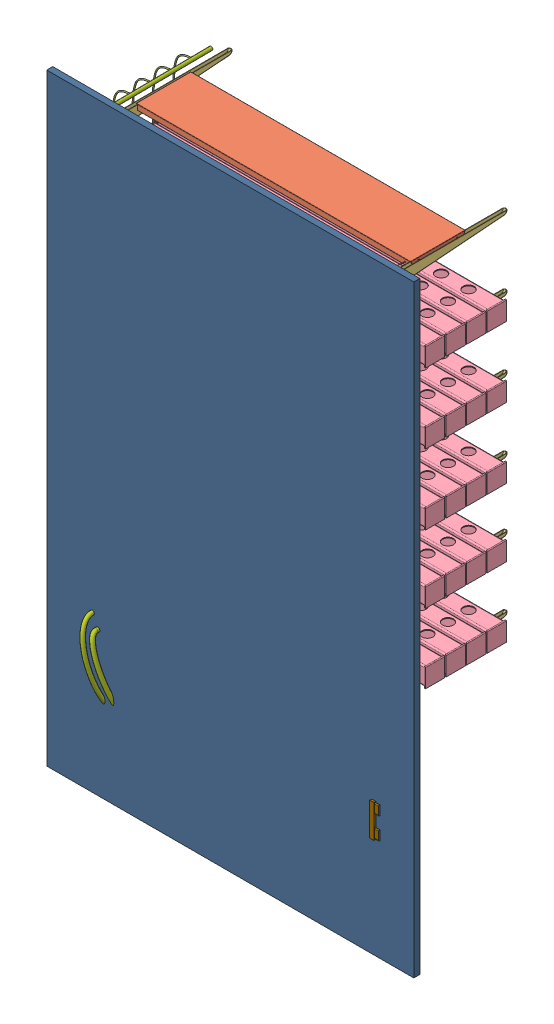
SolidWorks assembly C-W-1000, configuration Default. Lengths in mm.
Overall size (1339.66 2200 561.29).
63 component instances, 12 part files, 172 mates.
Components (placement in the parent):
- TSU-W-1: TSU-W [Default] at (502.4204 125.5072 -21.5071) size (25 1984 15)
- TSU-W-2: TSU-W [Default] at (-507.5796 125.5072 -25) size (25 1984 15)
- TSS-1000-10: TSS-1000 [Default] at (-2.5796 828.0993 -246.5218) size (1014.96 37.01 331.17)
- TSUB-1: TSUB [Default] at (502.4204 776.5993 -21.5071) x (-1 0 0) z (0 0 -1) size (14.07 50.86 484.03)
- TSUB-2: TSUB [Default] at (-507.5796 776.5993 -25) x (-1 0 0) z (0 0 -1) size (14.07 50.86 484.03)
- TSUB-3: TSUB [Default] at (-505 1030.7796 -25) x (-1 0 0) z (0 0 -1) size (14.07 50.86 484.03)
- TSUB-4: TSUB [Default] at (502.4801 1030.7796 -21.5071) x (-1 0 0) z (0 0 -1) size (14.07 50.86 484.03)
- TSS-1000-9: TSS-1000 [Default] at (-2.5199 1082.2796 -246.5218) size (1014.96 37.01 331.17)
- TSUB-5: TSUB [Default] at (-505 1534.5 -25) x (-1 0 0) z (0 0 -1) size (14.07 50.86 484.03)
- TSUB-6: TSUB [Default] at (502.4801 1534.5 -21.5071) x (-1 0 0) z (0 0 -1) size (14.07 50.86 484.03)
- TSS-1000-3: TSS-1000 [Default] at (-2.5199 1586 -246.5218) size (1014.96 37.01 331.17)
- TSUB-7: TSUB [Default] at (-505 2046.5 -25) x (-1 0 0) z (0 0 -1) size (14.07 50.86 484.03)
- TSUB-8: TSUB [Default] at (502.0186 2046.5 -21.5071) x (-1 0 0) z (0 0 -1) size (14.07 50.86 484.03)
- TSS-1000-7: TSS-1000 [Default] at (-2.9814 2098 -246.5218) size (1014.96 37.01 331.17)
- TSUB-9: TSUB [Default] at (-505 1278.5 -25) x (-1 0 0) z (0 0 -1) size (14.07 50.86 484.03)
- TSUB-10: TSUB [Default] at (502.4801 1278.5 -21.5071) x (-1 0 0) z (0 0 -1) size (14.07 50.86 484.03)
- TSS-1000-8: TSS-1000 [Default] at (-2.5199 1330 -246.5218) size (1014.96 37.01 331.17)
- TSUB-11: TSUB [Default] at (-505 1790.5 -25) x (-1 0 0) z (0 0 -1) size (14.07 50.86 484.03)
- TSUB-12: TSUB [Default] at (502.4801 1790.5 -21.5071) x (-1 0 0) z (0 0 -1) size (14.07 50.86 484.03)
- TSS-1000-6: TSS-1000 [Default] at (-2.5199 1842 -246.5218) size (1014.96 37.01 331.17)
- GB-1000-b-30: GB-1000-b [Default] at (0 1114.7796 -281.3342) size (1206 70 70)
- GB-600-p-1: GB-600-p [Default] at (-200 1114.7796 -281.3342) size (92 218.31 4)
- GB-600-p-2: GB-600-p [Default] at (-200 1114.7796 -356.3342) size (92 218.31 4)
- GB-1000-b-29: GB-1000-b [Default] at (0 1114.7796 -356.3342) size (1206 70 70)
- GB-600-p-3: GB-600-p [Default] at (-200 1114.7796 -131.3342) size (92 218.31 4)
- GB-1000-b-28: GB-1000-b [Default] at (0 1114.7796 -131.3342) size (1206 70 70)
- GB-600-p-4: GB-600-p [Default] at (-200 1114.7796 -206.3342) size (92 218.31 4)
- GB-1000-b-27: GB-1000-b [Default] at (0 1114.7796 -206.3342) size (1206 70 70)
- GB-1000-b-26: GB-1000-b [Default] at (0 860.5993 -131.3342) size (1206 70 70)
- GB-1000-b-25: GB-1000-b [Default] at (0 860.5993 -206.3342) size (1206 70 70)
- GB-1000-b-24: GB-1000-b [Default] at (0 860.5993 -281.3342) size (1206 70 70)
- GB-1000-b-23: GB-1000-b [Default] at (0 860.5993 -356.3342) size (1206 70 70)
- GB-1000-b-22: GB-1000-b [Default] at (0 1618.5 -131.3342) size (1206 70 70)
- GB-1000-b-15: GB-1000-b [Default] at (0 1618.5 -206.3342) size (1206 70 70)
- GB-1000-b-21: GB-1000-b [Default] at (0 1618.5 -281.3342) size (1206 70 70)
- GB-1000-b-31: GB-1000-b [Default] at (0 1618.5 -356.3342) size (1206 70 70)
- GB-600-p-5: GB-600-p [Default] at (-200 1618.5 -131.3342) size (92 218.31 4)
- GB-600-p-6: GB-600-p [Default] at (-200 1618.5 -206.3342) size (92 218.31 4)
- GB-600-p-7: GB-600-p [Default] at (-200 1618.5 -281.3342) size (92 218.31 4)
- GB-600-p-8: GB-600-p [Default] at (-200 1618.5 -356.3342) size (92 218.31 4)
- GB-600-p-9: GB-600-p [Default] at (-200 1362.5 -356.3342) size (92 218.31 4)
- GB-600-p-10: GB-600-p [Default] at (-200 1362.5 -281.3342) size (92 218.31 4)
- GB-600-p-11: GB-600-p [Default] at (-200 1362.5 -206.3342) size (92 218.31 4)
- GB-600-p-12: GB-600-p [Default] at (-200 1362.5 -131.3342) size (92 218.31 4)
- GB-1000-b-32: GB-1000-b [Default] at (0 1362.5 -356.3342) size (1206 70 70)
- GB-1000-b-38: GB-1000-b [Default] at (0 1362.5 -281.3342) size (1206 70 70)
- GB-1000-b-33: GB-1000-b [Default] at (0 1362.5 -206.3342) size (1206 70 70)
- GB-1000-b-34: GB-1000-b [Default] at (0 1362.5 -131.3342) size (1206 70 70)
- GB-600-p-13: GB-600-p [Default] at (-200 1874.5 -356.3342) size (92 218.31 4)
- GB-600-p-14: GB-600-p [Default] at (-200 1874.5 -281.3342) size (92 218.31 4)
- GB-600-p-15: GB-600-p [Default] at (-200 1874.5 -206.3342) size (92 218.31 4)
- GB-600-p-16: GB-600-p [Default] at (-200 1874.5 -131.3342) size (92 218.31 4)
- GB-1000-b-35: GB-1000-b [Default] at (0 1874.5 -131.3342) size (1206 70 70)
- GB-1000-b-36: GB-1000-b [Default] at (0 1874.5 -206.3342) size (1206 70 70)
- GB-1000-b-37: GB-1000-b [Default] at (0 1874.5 -281.3342) size (1206 70 70)
- GB-1000-b-39: GB-1000-b [Default] at (0 1874.5 -356.3342) size (1206 70 70)
- WT-1: WT [Default] at (-201.8616 320 -221.5071) size (600 370 400)
- Plumbing-1: Plumbing [Default] at (-504.0362 123.4725 -23.2262) x (0.99996 0 -0.008889) z (0.008889 0 0.99996) size (241.4 2067.5 489.85)
- Wire-1: Wire [Default] at (205.8727 2074.2018 -246.5277) x (-1 0 0) z (0 -1 0) size (2 2 1357)
- CCD-1: CCD [Default] at (502.4204 125.5072 -21.5071) x (0 0 -1) z (1 0 0) size (82.56 307.09 97.63) (hidden)
- Pump_LongWire-1: Pump_LongWire [Default] at (-201.8616 5 -221.5071) x (1 0 0) z (0 1 0) size (1045.87 220.37 364.08) (hidden)
- power brick-1: power brick [Default] at (516.0203 148.5195 -25) x (0 0 -1) z (1 0 0) size (82.62 120 30)
- Part2^C-W-1000-1: Part2^C-W-1000 [Default] x (1 0 0) z (0 1 0) size (1339.66 21.96 2200) (virtual)
Mates (geometry in assembly coordinates):
- Coincident41: coincident anti-aligned: plane of TSU-W-1 through (495.4204 797.5072 -6.5071) normal (1 0 0); plane of TSUB-1 through (495.4204 776.5993 -21.5071) normal (-1 0 0)
- Coincident42: coincident anti-aligned: plane of TSU-W-1 through (502.4204 2109.5072 -21.5071) normal (0 0 -1); plane of TSUB-1 through (509.4204 776.5993 -21.5071) normal (0 0 1)
- Parallel8: parallel: line of TSU-F-L-P-1 through (509 342 -23.5) axis (0 0 -1); plane of TSUB-1 through (498 816.5 -25) normal (0 1 0)
- Coincident44: coincident anti-aligned: plane of TSS-1000-10 through (496.9204 808.0993 -246.5218) normal (-1 0 0); plane of TSUB-1 through (496.9204 776.5993 -21.5071) normal (1 0 0)
- Coincident45: coincident anti-aligned: plane of TSS-1000-10 through (498.4204 826.5993 -148.0218) normal (0 -1 0); plane of TSUB-1 through (495.4204 826.5993 -21.5071) normal (0 1 0)
- Coincident46: coincident anti-aligned: plane of TSU-W-2 through (-514.5796 765.5072 -10) normal (1 0 0); plane of TSUB-2 through (-514.5796 776.5993 -25) normal (-1 0 0)
- Coincident47: coincident anti-aligned: plane of TSU-W-2 through (-507.5796 2109.5072 -25) normal (0 0 -1); plane of TSUB-2 through (-514.5796 776.5993 -25) normal (0 0 1)
- Coincident48: coincident anti-aligned: plane of TSS-1000-10 through (498.4204 826.5993 -148.0218) normal (0 -1 0); plane of TSUB-2 through (-514.5796 826.5993 -25) normal (0 1 0)
- Coincident49: coincident: plane of TSU-F-L-P-1 through (512 1041.5 0.001) normal (-1 0 0); plane of TSUB-4 through (512 1022.5 -25) normal (1 0 0)
- Coincident50: coincident anti-aligned: plane of TSU-W-1 through (502.4204 2109.5072 -21.5071) normal (0 0 -1); plane of TSUB-4 through (509.4801 1030.7796 -21.5071) normal (0 0 1)
- Coincident51: coincident: plane of TSU-F-L-P-2 through (-498 1073.5 0.001) normal (-1 0 0); plane of TSUB-3 through (-498 1022.5 -25) normal (1 0 0)
- Coincident52: coincident anti-aligned: plane of TSU-W-2 through (-507.5796 2109.5072 -25) normal (0 0 -1); plane of TSUB-3 through (-512 1030.7796 -25) normal (0 0 1)
- Coincident53: coincident anti-aligned: plane of TSUB-4 through (495.4801 1080.7796 -21.5071) normal (0 1 0); plane of TSS-1000-9 through (498.4801 1080.7796 -148.0218) normal (0 -1 0)
- Coincident54: coincident anti-aligned: plane of TSUB-3 through (-512 1080.7796 -25) normal (0 1 0); plane of TSS-1000-9 through (498.4801 1080.7796 -148.0218) normal (0 -1 0)
- Coincident55: coincident anti-aligned: plane of TSUB-4 through (496.9801 1030.7796 -21.5071) normal (1 0 0); plane of TSS-1000-9 through (496.9801 1062.2796 -246.5218) normal (-1 0 0)
- Coincident56: coincident anti-aligned: plane of TSUB-6 through (496.9801 1534.5 -21.5071) normal (1 0 0); plane of TSS-1000-3 through (496.9801 1566 -246.5218) normal (-1 0 0)
- Coincident57: coincident anti-aligned: plane of TSUB-6 through (495.4801 1584.5 -21.5071) normal (0 1 0); plane of TSS-1000-3 through (498.4801 1584.5 -148.0218) normal (0 -1 0)
- Coincident58: coincident anti-aligned: plane of TSUB-5 through (-512 1584.5 -25) normal (0 1 0); plane of TSS-1000-3 through (498.4801 1584.5 -148.0218) normal (0 -1 0)
- Coincident59: coincident anti-aligned: plane of TSUB-8 through (496.5186 2046.5 -21.5071) normal (1 0 0); plane of TSS-1000-7 through (496.5186 2078 -246.5218) normal (-1 0 0)
- Coincident60: coincident anti-aligned: plane of TSUB-8 through (495.0186 2096.5 -21.5071) normal (0 1 0); plane of TSS-1000-7 through (498.0186 2096.5 -148.0218) normal (0 -1 0)
- Coincident61: coincident anti-aligned: plane of TSUB-7 through (-512 2096.5 -25) normal (0 1 0); plane of TSS-1000-7 through (498.0186 2096.5 -148.0218) normal (0 -1 0)
- Coincident62: coincident anti-aligned: plane of TSUB-10 through (496.9801 1278.5 -21.5071) normal (1 0 0); plane of TSS-1000-8 through (496.9801 1310 -246.5218) normal (-1 0 0)
- Coincident63: coincident anti-aligned: plane of TSUB-10 through (495.4801 1328.5 -21.5071) normal (0 1 0); plane of TSS-1000-8 through (498.4801 1328.5 -148.0218) normal (0 -1 0)
- Coincident64: coincident anti-aligned: plane of TSUB-9 through (-512 1328.5 -25) normal (0 1 0); plane of TSS-1000-8 through (498.4801 1328.5 -148.0218) normal (0 -1 0)
- Coincident65: coincident anti-aligned: plane of TSUB-12 through (496.9801 1790.5 -21.5071) normal (1 0 0); plane of TSS-1000-6 through (496.9801 1822 -246.5218) normal (-1 0 0)
- Coincident66: coincident anti-aligned: plane of TSUB-12 through (495.4801 1840.5 -21.5071) normal (0 1 0); plane of TSS-1000-6 through (498.4801 1840.5 -148.0218) normal (0 -1 0)
- Coincident67: coincident anti-aligned: plane of TSUB-11 through (-512 1840.5 -25) normal (0 1 0); plane of TSS-1000-6 through (498.4801 1840.5 -148.0218) normal (0 -1 0)
- Coincident70: coincident anti-aligned: plane of TSU-W-1 through (502.4204 2109.5072 -21.5071) normal (0 0 -1); plane of TSUB-10 through (495.4801 1278.5 -21.5071) normal (0 0 1)
- Coincident71: coincident anti-aligned: plane of TSU-W-2 through (-507.5796 2109.5072 -25) normal (0 0 -1); plane of TSUB-9 through (-512 1278.5 -25) normal (0 0 1)
- Coincident72: coincident aligned: plane of TSUB-3 through (-498 1030.7796 -25) normal (1 0 0); plane of TSUB-9 through (-498 1278.5 -25) normal (1 0 0)
- Coincident73: coincident aligned: plane of TSUB-4 through (495.4801 1030.7796 -21.5071) normal (-1 0 0); plane of TSUB-10 through (495.4801 1278.5 -21.5071) normal (-1 0 0)
- Coincident74: coincident anti-aligned: plane of TSU-W-1 through (502.4204 2109.5072 -21.5071) normal (0 0 -1); plane of TSUB-6 through (495.4801 1534.5 -21.5071) normal (0 0 1)
- Coincident75: coincident anti-aligned: plane of TSU-W-2 through (-507.5796 2109.5072 -25) normal (0 0 -1); plane of TSUB-5 through (-512 1534.5 -25) normal (0 0 1)
- Coincident76: coincident aligned: plane of TSUB-5 through (-498 1534.5 -25) normal (1 0 0); plane of TSUB-9 through (-498 1278.5 -25) normal (1 0 0)
- Coincident78: coincident aligned: plane of TSUB-6 through (509.4801 1534.5 -21.5071) normal (1 0 0); plane of TSUB-12 through (509.4801 1790.5 -21.5071) normal (1 0 0)
- Coincident79: coincident aligned: plane of TSUB-6 through (495.4801 1534.5 -21.5071) normal (-1 0 0); plane of TSUB-10 through (495.4801 1278.5 -21.5071) normal (-1 0 0)
- Coincident80: coincident anti-aligned: plane of TSU-W-1 through (502.4204 2109.5072 -21.5071) normal (0 0 -1); plane of TSUB-12 through (495.4801 1790.5 -21.5071) normal (0 0 1)
- Coincident81: coincident: plane of TSU-F-L-P-2 through (-512 1873.5 0.001) normal (1 0 0); plane of TSUB-11 through (-512 1790.5 -25) normal (-1 0 0)
- Coincident82: coincident anti-aligned: plane of TSU-W-2 through (-507.5796 2109.5072 -25) normal (0 0 -1); plane of TSUB-11 through (-512 1790.5 -25) normal (0 0 1)
- Coincident83: coincident: plane of TSU-F-L-P-2 through (-512 1969.5 0.001) normal (1 0 0); plane of TSUB-7 through (-512 2046.5 -25) normal (-1 0 0)
- Coincident84: coincident anti-aligned: plane of TSU-W-2 through (-507.5796 2109.5072 -25) normal (0 0 -1); plane of TSUB-7 through (-512 2046.5 -25) normal (0 0 1)
- Coincident85: coincident: plane of TSU-F-L-P-1 through (498 2001.5 0.001) normal (1 0 0); plane of TSUB-8 through (498 2046.5 -25) normal (-1 0 0)
- Coincident86: coincident anti-aligned: plane of TSU-W-1 through (502.4204 2109.5072 -21.5071) normal (0 0 -1); plane of TSUB-8 through (495.0186 2046.5 -21.5071) normal (0 0 1)
- Coincident89: coincident: line of TSU-F-L-P-1 through (509 2070 -23.5) axis (0 0 -1); plane of TSUB-8 through (533.2603 2070 -25) normal (0 1 0)
- Coincident90: coincident aligned: plane of TSS-1000-7 through (498.0186 2098 -346.5218) normal (0 0 -1); plane of TSS-1000-6 through (498.4801 1842 -346.5218) normal (0 0 -1)
- Coincident91: coincident aligned: plane of TSS-1000-3 through (498.4801 1586 -346.5218) normal (0 0 -1); plane of TSS-1000-6 through (498.4801 1842 -346.5218) normal (0 0 -1)
- Coincident93: coincident aligned: plane of TSS-1000-3 through (498.4801 1586 -346.5218) normal (0 0 -1); plane of TSS-1000-8 through (498.4801 1330 -346.5218) normal (0 0 -1)
- Coincident94: coincident aligned: plane of TSS-1000-9 through (498.4801 1082.2796 -346.5218) normal (0 0 -1); plane of TSS-1000-8 through (498.4801 1330 -346.5218) normal (0 0 -1)
- Coincident95: coincident aligned: plane of TSS-1000-10 through (498.4204 828.0993 -346.5218) normal (0 0 -1); plane of TSS-1000-9 through (498.4801 1082.2796 -346.5218) normal (0 0 -1)
- Coincident153: coincident: line of TSU-F-L-P-1 through (512 1814 -23.5) axis (0 0 -1); plane of TSUB-12 through (533.2603 1814 -25) normal (0 1 0)
- Coincident155: coincident: line of TSU-F-L-P-1 through (512 1558 -23.5) axis (0 0 -1); plane of TSUB-6 through (533.2603 1558 -25) normal (0 1 0)
- Coincident157: coincident: line of TSU-F-L-P-1 through (512 1302 -23.5) axis (0 0 -1); plane of TSUB-10 through (533.2603 1302 -25) normal (0 1 0)
- Coincident159: coincident: line of TSU-F-L-P-1 through (512 1046 -23.5) axis (0 0 -1); plane of TSUB-4 through (533.2603 1046 -25) normal (0 1 0)
- Coincident167: coincident: line of TSU-F-L-P-1 through (512 790 -23.5) axis (0 0 -1); plane of TSUB-1 through (533.2603 790 -25) normal (0 1 0)
- Concentric31: concentric aligned: cylinder of GB-1000-b-24 through (-575 825.5983 -281.3342) axis (0 1 0) radius 4; cylinder of GB-600-p-1 through (-575 885.2796 -281.3342) axis (0 1 0) radius 2
- Distance1: distance = 10 mm aligned: plane of GB-600-p-1 through (-575 1095.2796 -281.3342) normal (0 1 0); plane of GB-1000-b-30 through (600 1085.2796 -248.8342) normal (0 1 0)
- Parallel10: parallel anti-aligned: plane of TSU-W-1 through (502.4204 2109.5072 -21.5071) normal (0 0 -1); plane of GB-1000-b-30 through (600 1082.2796 -248.8342) normal (0 0 1)
- Coincident201: coincident aligned: plane of GB-1000-b-30 through (0 1114.7796 -281.3342) normal (1 0 0)
- Coincident202: coincident anti-aligned: plane of TSS-1000-9 through (498.4801 1082.2796 -146.5218) normal (0 1 0); plane of GB-1000-b-30 through (600 1082.2796 -248.8342) normal (0 -1 0)
- Concentric32: concentric aligned: cylinder of GB-600-p-2 through (-575 885.2796 -356.3342) axis (0 1 0) radius 2; cylinder of GB-1000-b-29 through (-575 1079.7786 -356.3342) axis (0 1 0) radius 4
- Distance2: distance = 10 mm aligned: plane of GB-600-p-2 through (-575 1095.2796 -356.3342) normal (0 1 0); plane of GB-1000-b-29 through (600 1085.2796 -323.8342) normal (0 1 0)
- Concentric33: concentric aligned: cylinder of GB-600-p-3 through (-575 885.2796 -131.3342) axis (0 1 0) radius 2; cylinder of GB-1000-b-28 through (-575 1079.7786 -131.3342) axis (0 1 0) radius 4
- Distance3: distance = 10 mm aligned: plane of GB-600-p-3 through (-575 1095.2796 -131.3342) normal (0 1 0); plane of GB-1000-b-28 through (600 1085.2796 -98.8342) normal (0 1 0)
- Concentric34: concentric aligned: cylinder of GB-600-p-4 through (-575 885.2796 -206.3342) axis (0 1 0) radius 2; cylinder of GB-1000-b-27 through (-575 1079.7786 -206.3342) axis (0 1 0) radius 4
- Distance4: distance = 10 mm aligned: plane of GB-600-p-4 through (-575 1095.2796 -206.3342) normal (0 1 0); plane of GB-1000-b-27 through (600 1085.2796 -173.8342) normal (0 1 0)
- Coincident203: coincident anti-aligned: plane of TSS-1000-9 through (498.4801 1082.2796 -146.5218) normal (0 1 0); plane of GB-1000-b-29 through (600 1082.2796 -323.8342) normal (0 -1 0)
- Coincident204: coincident anti-aligned: plane of TSS-1000-9 through (498.4801 1082.2796 -146.5218) normal (0 1 0); plane of GB-1000-b-27 through (600 1082.2796 -173.8342) normal (0 -1 0)
- Coincident205: coincident anti-aligned: plane of TSS-1000-9 through (498.4801 1082.2796 -146.5218) normal (0 1 0); plane of GB-1000-b-28 through (600 1082.2796 -98.8342) normal (0 -1 0)
- Coincident206: coincident aligned: plane of GB-1000-b-30 through (603 1114.7796 -281.3342) normal (1 0 0); plane of GB-1000-b-27 through (603 1114.7796 -206.3342) normal (1 0 0)
- Coincident207: coincident aligned: plane of GB-1000-b-28 through (603 1114.7796 -131.3342) normal (1 0 0); plane of GB-1000-b-27 through (603 1114.7796 -206.3342) normal (1 0 0)
- Coincident208: coincident aligned: plane of GB-1000-b-30 through (603 1114.7796 -281.3342) normal (1 0 0); plane of GB-1000-b-29 through (603 1114.7796 -356.3342) normal (1 0 0)
- Distance5: distance = 10 mm anti-aligned: plane of GB-1000-b-27 through (600 1082.2796 -238.8342) normal (0 0 -1); plane of GB-1000-b-30 through (600 1082.2796 -248.8342) normal (0 0 1)
- Distance6: distance = 10 mm anti-aligned: plane of GB-1000-b-27 through (600 1082.2796 -173.8342) normal (0 0 1); plane of GB-1000-b-28 through (600 1082.2796 -163.8342) normal (0 0 -1)
- Distance7: distance = 10 mm anti-aligned: plane of GB-1000-b-30 through (600 1082.2796 -313.8342) normal (0 0 -1); plane of GB-1000-b-29 through (600 1082.2796 -323.8342) normal (0 0 1)
- Distance8: distance = 10 mm anti-aligned: plane of GB-1000-b-25 through (600 828.0993 -173.8342) normal (0 0 1); plane of GB-1000-b-26 through (600 828.0993 -163.8342) normal (0 0 -1)
- Distance9: distance = 10 mm anti-aligned: plane of GB-1000-b-25 through (600 828.0993 -238.8342) normal (0 0 -1); plane of GB-1000-b-24 through (600 828.0993 -248.8342) normal (0 0 1)
- Coincident212: coincident aligned: plane of GB-1000-b-26 through (603 860.5993 -131.3342) normal (1 0 0); plane of GB-1000-b-25 through (603 860.5993 -206.3342) normal (1 0 0)
- Coincident213: coincident aligned: plane of GB-1000-b-24 through (603 860.5993 -281.3342) normal (1 0 0); plane of GB-1000-b-23 through (603 860.5993 -356.3342) normal (1 0 0)
- Coincident214: coincident aligned: plane of GB-1000-b-25 through (603 860.5993 -206.3342) normal (1 0 0); plane of GB-1000-b-24 through (603 860.5993 -281.3342) normal (1 0 0)
- Distance10: distance = 10 mm anti-aligned: plane of GB-1000-b-24 through (600 828.0993 -313.8342) normal (0 0 -1); plane of GB-1000-b-23 through (600 828.0993 -323.8342) normal (0 0 1)
- Coincident215: coincident aligned: plane of GB-1000-b-24 through (600 828.0993 -248.8342) normal (0 -1 0); plane of GB-1000-b-23 through (600 828.0993 -323.8342) normal (0 -1 0)
- Coincident216: coincident aligned: plane of GB-1000-b-25 through (600 828.0993 -173.8342) normal (0 -1 0); plane of GB-1000-b-24 through (600 828.0993 -248.8342) normal (0 -1 0)
- Coincident217: coincident aligned: plane of GB-1000-b-26 through (600 828.0993 -98.8342) normal (0 -1 0); plane of GB-1000-b-25 through (600 828.0993 -173.8342) normal (0 -1 0)
- Coincident218: coincident anti-aligned: plane of TSS-1000-10 through (498.4204 828.0993 -146.5218) normal (0 1 0); plane of GB-1000-b-24 through (600 828.0993 -248.8342) normal (0 -1 0)
- Concentric35: concentric aligned: cylinder of GB-600-p-2 through (-575 885.2796 -356.3342) axis (0 1 0) radius 2; cylinder of GB-1000-b-23 through (-575 825.5983 -356.3342) axis (0 1 0) radius 4
- Concentric36: concentric aligned: cylinder of GB-1000-b-22 through (-575 1583.499 -131.3342) axis (0 1 0) radius 4; cylinder of GB-600-p-5 through (-575 1389 -131.3342) axis (0 1 0) radius 2
- Distance11: distance = 10 mm anti-aligned: plane of GB-1000-b-15 through (600 1586 -173.8342) normal (0 0 1); plane of GB-1000-b-22 through (600 1586 -163.8342) normal (0 0 -1)
- Concentric37: concentric aligned: cylinder of GB-1000-b-31 through (-575 1583.499 -356.3342) axis (0 1 0) radius 4; cylinder of GB-600-p-8 through (-575 1389 -356.3342) axis (0 1 0) radius 2
- Concentric38: concentric aligned: cylinder of GB-1000-b-21 through (-575 1583.499 -281.3342) axis (0 1 0) radius 4; cylinder of GB-600-p-7 through (-575 1389 -281.3342) axis (0 1 0) radius 2
- Distance12: distance = 10 mm aligned: plane of GB-600-p-7 through (-575 1599 -281.3342) normal (0 1 0); plane of GB-1000-b-21 through (600 1589 -248.8342) normal (0 1 0)
- Distance13: distance = 10 mm anti-aligned: plane of GB-1000-b-15 through (600 1586 -238.8342) normal (0 0 -1); plane of GB-1000-b-21 through (600 1586 -248.8342) normal (0 0 1)
- Concentric39: concentric aligned: cylinder of GB-1000-b-15 through (-575 1583.499 -206.3342) axis (0 1 0) radius 4; cylinder of GB-600-p-6 through (-575 1389 -206.3342) axis (0 1 0) radius 2
- Distance14: distance = 10 mm aligned: plane of GB-600-p-8 through (-575 1599 -356.3342) normal (0 1 0); plane of GB-1000-b-31 through (600 1589 -323.8342) normal (0 1 0)
- Distance15: distance = 10 mm aligned: plane of GB-600-p-5 through (-575 1599 -131.3342) normal (0 1 0); plane of GB-1000-b-22 through (600 1589 -98.8342) normal (0 1 0)
- Distance16: distance = 10 mm aligned: plane of GB-600-p-6 through (-575 1599 -206.3342) normal (0 1 0); plane of GB-1000-b-15 through (600 1589 -173.8342) normal (0 1 0)
- Coincident220: coincident aligned: plane of GB-1000-b-22 through (603 1618.5 -131.3342) normal (1 0 0); plane of GB-1000-b-15 through (603 1618.5 -206.3342) normal (1 0 0)
- Coincident221: coincident aligned: plane of GB-1000-b-21 through (603 1618.5 -281.3342) normal (1 0 0); plane of GB-1000-b-31 through (603 1618.5 -356.3342) normal (1 0 0)
- Coincident222: coincident aligned: plane of GB-1000-b-15 through (603 1618.5 -206.3342) normal (1 0 0); plane of GB-1000-b-21 through (603 1618.5 -281.3342) normal (1 0 0)
- Distance17: distance = 10 mm anti-aligned: plane of GB-1000-b-21 through (600 1586 -313.8342) normal (0 0 -1); plane of GB-1000-b-31 through (600 1586 -323.8342) normal (0 0 1)
- Coincident223: coincident aligned: plane of GB-1000-b-31 through (600 1586 -323.8342) normal (0 -1 0); plane of GB-1000-b-22 through (600 1586 -98.8342) normal (0 -1 0)
- Coincident224: coincident aligned: plane of GB-1000-b-22 through (600 1586 -98.8342) normal (0 -1 0); plane of GB-1000-b-15 through (600 1586 -173.8342) normal (0 -1 0)
- Coincident225: coincident aligned: plane of GB-1000-b-15 through (600 1586 -173.8342) normal (0 -1 0); plane of GB-1000-b-21 through (600 1586 -248.8342) normal (0 -1 0)
- Coincident226: coincident aligned: plane of GB-1000-b-33 through (600 1330 -173.8342) normal (0 -1 0); plane of GB-1000-b-34 through (600 1330 -98.8342) normal (0 -1 0)
- Coincident227: coincident aligned: plane of GB-1000-b-38 through (600 1330 -248.8342) normal (0 -1 0); plane of GB-1000-b-33 through (600 1330 -173.8342) normal (0 -1 0)
- Coincident228: coincident aligned: plane of GB-1000-b-38 through (603 1362.5 -281.3342) normal (1 0 0); plane of GB-1000-b-33 through (603 1362.5 -206.3342) normal (1 0 0)
- Distance18: distance = 10 mm anti-aligned: plane of GB-1000-b-38 through (600 1330 -313.8342) normal (0 0 -1); plane of GB-1000-b-32 through (600 1330 -323.8342) normal (0 0 1)
- Coincident229: coincident aligned: plane of GB-1000-b-32 through (600 1330 -323.8342) normal (0 -1 0); plane of GB-1000-b-34 through (600 1330 -98.8342) normal (0 -1 0)
- Concentric40: concentric aligned: cylinder of GB-600-p-10 through (-575 1133 -281.3342) axis (0 1 0) radius 2; cylinder of GB-1000-b-38 through (-575 1327.499 -281.3342) axis (0 1 0) radius 4
- Distance19: distance = 10 mm aligned: plane of GB-600-p-11 through (-575 1343 -206.3342) normal (0 1 0); plane of GB-1000-b-33 through (600 1333 -173.8342) normal (0 1 0)
- Concentric41: concentric aligned: cylinder of GB-600-p-12 through (-575 1133 -131.3342) axis (0 1 0) radius 2; cylinder of GB-1000-b-34 through (-575 1327.499 -131.3342) axis (0 1 0) radius 4
- Distance20: distance = 10 mm aligned: plane of GB-600-p-12 through (-575 1343 -131.3342) normal (0 1 0); plane of GB-1000-b-34 through (600 1333 -98.8342) normal (0 1 0)
- Distance21: distance = 10 mm anti-aligned: plane of GB-1000-b-33 through (600 1330 -173.8342) normal (0 0 1); plane of GB-1000-b-34 through (600 1330 -163.8342) normal (0 0 -1)
- Coincident230: coincident aligned: plane of GB-1000-b-33 through (603 1362.5 -206.3342) normal (1 0 0); plane of GB-1000-b-34 through (603 1362.5 -131.3342) normal (1 0 0)
- Distance22: distance = 10 mm anti-aligned: plane of GB-1000-b-33 through (600 1330 -238.8342) normal (0 0 -1); plane of GB-1000-b-38 through (600 1330 -248.8342) normal (0 0 1)
- Concentric42: concentric aligned: cylinder of GB-600-p-9 through (-575 1133 -356.3342) axis (0 1 0) radius 2; cylinder of GB-1000-b-32 through (-575 1327.499 -356.3342) axis (0 1 0) radius 4
- Distance23: distance = 10 mm aligned: plane of GB-600-p-9 through (-575 1343 -356.3342) normal (0 1 0); plane of GB-1000-b-32 through (600 1333 -323.8342) normal (0 1 0)
- Distance24: distance = 10 mm aligned: plane of GB-600-p-10 through (-575 1343 -281.3342) normal (0 1 0); plane of GB-1000-b-38 through (600 1333 -248.8342) normal (0 1 0)
- Concentric43: concentric aligned: cylinder of GB-600-p-11 through (-575 1133 -206.3342) axis (0 1 0) radius 2; cylinder of GB-1000-b-33 through (-575 1327.499 -206.3342) axis (0 1 0) radius 4
- Coincident231: coincident aligned: plane of GB-1000-b-32 through (603 1362.5 -356.3342) normal (1 0 0); plane of GB-1000-b-38 through (603 1362.5 -281.3342) normal (1 0 0)
- Coincident232: coincident anti-aligned: plane of TSS-1000-8 through (498.4801 1330 -146.5218) normal (0 1 0); plane of GB-1000-b-32 through (600 1330 -323.8342) normal (0 -1 0)
- Coincident233: coincident aligned: plane of GB-1000-b-29 through (600 1082.2796 -388.8342) normal (0 0 -1); plane of GB-1000-b-32 through (600 1330 -388.8342) normal (0 0 -1)
- Coincident234: coincident aligned: plane of GB-1000-b-29 through (603 1114.7796 -356.3342) normal (1 0 0); plane of GB-1000-b-32 through (603 1362.5 -356.3342) normal (1 0 0)
- Coincident235: coincident anti-aligned: plane of TSS-1000-3 through (498.4801 1586 -146.5218) normal (0 1 0); plane of GB-1000-b-31 through (600 1586 -323.8342) normal (0 -1 0)
- Coincident236: coincident aligned: plane of GB-1000-b-32 through (-603 1362.5 -356.3342) normal (-1 0 0); plane of GB-1000-b-31 through (-603 1618.5 -356.3342) normal (-1 0 0)
- Coincident237: coincident aligned: plane of GB-1000-b-31 through (600 1586 -388.8342) normal (0 0 -1); plane of GB-1000-b-32 through (600 1330 -388.8342) normal (0 0 -1)
- Coincident238: coincident aligned: plane of GB-1000-b-35 through (600 1842 -98.8342) normal (0 -1 0); plane of GB-1000-b-36 through (600 1842 -173.8342) normal (0 -1 0)
- Coincident239: coincident aligned: plane of GB-1000-b-36 through (600 1842 -173.8342) normal (0 -1 0); plane of GB-1000-b-37 through (600 1842 -248.8342) normal (0 -1 0)
- Coincident240: coincident aligned: plane of GB-1000-b-36 through (603 1874.5 -206.3342) normal (1 0 0); plane of GB-1000-b-37 through (603 1874.5 -281.3342) normal (1 0 0)
- Distance25: distance = 10 mm anti-aligned: plane of GB-1000-b-37 through (600 1842 -313.8342) normal (0 0 -1); plane of GB-1000-b-39 through (600 1842 -323.8342) normal (0 0 1)
- Coincident241: coincident aligned: plane of GB-1000-b-35 through (600 1842 -98.8342) normal (0 -1 0); plane of GB-1000-b-39 through (600 1842 -323.8342) normal (0 -1 0)
- Concentric44: concentric aligned: cylinder of GB-600-p-14 through (-575 1645 -281.3342) axis (0 1 0) radius 2; cylinder of GB-1000-b-37 through (-575 1839.499 -281.3342) axis (0 1 0) radius 4
- Distance26: distance = 10 mm aligned: plane of GB-600-p-15 through (-575 1855 -206.3342) normal (0 1 0); plane of GB-1000-b-36 through (600 1845 -173.8342) normal (0 1 0)
- Concentric45: concentric aligned: cylinder of GB-600-p-16 through (-575 1645 -131.3342) axis (0 1 0) radius 2; cylinder of GB-1000-b-35 through (-575 1839.499 -131.3342) axis (0 1 0) radius 4
- Distance27: distance = 10 mm aligned: plane of GB-600-p-16 through (-575 1855 -131.3342) normal (0 1 0); plane of GB-1000-b-35 through (600 1845 -98.8342) normal (0 1 0)
- Distance28: distance = 10 mm anti-aligned: plane of GB-1000-b-36 through (600 1842 -173.8342) normal (0 0 1); plane of GB-1000-b-35 through (600 1842 -163.8342) normal (0 0 -1)
- Coincident242: coincident aligned: plane of GB-1000-b-35 through (603 1874.5 -131.3342) normal (1 0 0); plane of GB-1000-b-36 through (603 1874.5 -206.3342) normal (1 0 0)
- Distance29: distance = 10 mm anti-aligned: plane of GB-1000-b-36 through (600 1842 -238.8342) normal (0 0 -1); plane of GB-1000-b-37 through (600 1842 -248.8342) normal (0 0 1)
- Concentric46: concentric aligned: cylinder of GB-600-p-13 through (-575 1645 -356.3342) axis (0 1 0) radius 2; cylinder of GB-1000-b-39 through (-575 1839.499 -356.3342) axis (0 1 0) radius 4
- Distance30: distance = 10 mm aligned: plane of GB-600-p-13 through (-575 1855 -356.3342) normal (0 1 0); plane of GB-1000-b-39 through (600 1845 -323.8342) normal (0 1 0)
- Distance31: distance = 10 mm aligned: plane of GB-600-p-14 through (-575 1855 -281.3342) normal (0 1 0); plane of GB-1000-b-37 through (600 1845 -248.8342) normal (0 1 0)
- Concentric47: concentric aligned: cylinder of GB-600-p-15 through (-575 1645 -206.3342) axis (0 1 0) radius 2; cylinder of GB-1000-b-36 through (-575 1839.499 -206.3342) axis (0 1 0) radius 4
- Coincident243: coincident aligned: plane of GB-1000-b-37 through (603 1874.5 -281.3342) normal (1 0 0); plane of GB-1000-b-39 through (603 1874.5 -356.3342) normal (1 0 0)
- Coincident244: coincident anti-aligned: plane of TSS-1000-6 through (498.4801 1842 -146.5218) normal (0 1 0); plane of GB-1000-b-39 through (600 1842 -323.8342) normal (0 -1 0)
- Coincident245: coincident aligned: plane of GB-1000-b-31 through (600 1586 -388.8342) normal (0 0 -1); plane of GB-1000-b-39 through (600 1842 -388.8342) normal (0 0 -1)
- Coincident246: coincident aligned: plane of GB-1000-b-31 through (-603 1618.5 -356.3342) normal (-1 0 0); plane of GB-1000-b-39 through (-603 1874.5 -356.3342) normal (-1 0 0)
- Coincident247: coincident anti-aligned: plane of Part3-1 through (-201.8616 0 -221.5071) normal (0 -1 0)
- Coincident249: coincident anti-aligned: plane of TSU-W-1 through (502.4204 2109.5072 -21.5071) normal (0 0 -1); plane of Part3-1 through (-201.8616 370 -21.5071) normal (0 0 1)
- Coincident250: coincident aligned: plane of GB-1000-b-29 through (603 1114.7796 -356.3342) normal (1 0 0); plane of GB-1000-b-23 through (603 860.5993 -356.3342) normal (1 0 0)
- InPlace3: in place: plane of ? through (305 113.5 -25) normal (1 0 0); plane of ? through (305 113.5 -25) normal (1 0 0); moOrthogonalPlaneRef_w of ? through (305 113.5 -25) normal (1 0 0); plane of ? through (305 113.5 -25) normal (0 1 0); plane of ? through (305 113.5 -25) normal (1 0 0); plane of ? through (305 113.5 -25) normal (0 0 -1); plane of TSU-W-1 through (502.4204 125.5072 -21.5071) normal (1 0 0); unknown of CCD-1
- Coincident254: coincident aligned: plane of ?; plane of CCD-1
- Coincident255: coincident aligned: moOrthogonalPlaneRef_w of TSU-W-1; plane of Part2-1 through (502.4204 125.5072 -21.5071) normal (0 1 0)
- Coincident256: coincident anti-aligned: moOrthogonalPlaneRef_w of TSU-W-1 through (-21.5071 0 0) axis (1 0 0); plane of Part2-1 through (502.4204 125.5072 -21.5071) normal (0 0 -1)
- InPlace4: in place: plane of ? through (0 5 -225) normal (0 1 0); plane of ? through (0 5 0) normal (0 1 0); plane of ? through (0 5 -225) normal (0 1 0); plane of ? through (0 5 0) normal (0 0 -1); plane of ? through (0 5 -225) normal (0 1 0); plane of ? through (0 5 0) normal (1 0 0); plane of WT-1 through (-201.8616 5 -221.5071) normal (0 1 0); unknown of Pump_LongWire-1
- Coincident257: coincident aligned: plane of WT-1; plane of Pump_LongWire-1
- Coincident258: coincident aligned: moOrthogonalPlaneRef_w of Part3-1 through (-201.8616 5 -221.5071) normal (0 0 -1); plane of ele2-1 through (-201.8616 5 -221.5071) normal (0 0 -1)
- Coincident259: coincident anti-aligned: moOrthogonalPlaneRef_w of Part3-1 through (-201.8616 5 -221.5071) normal (-1 0 0); plane of ele2-1 through (-201.8616 5 -221.5071) normal (1 0 0)
- InPlace5: in place: plane of ? through (317.5 2113.5 -22) normal (1 0 0); plane of ? through (317.5 0 0) normal (1 0 0); plane of ? through (317.5 2113.5 -22) normal (1 0 0); plane of ? through (317.5 0 0) normal (0 1 0); plane of ? through (317.5 2113.5 -22) normal (1 0 0); plane of ? through (317.5 0 0) normal (0 0 -1); plane of ? through (517.5 2113.5 -22) normal (1 0 0); unknown of ?
- Coincident260: coincident aligned: plane of ?; plane of power brick-1
- Coincident261: coincident aligned: moOrthogonalPlaneRef_w of TSU-F-L-P-1 through (517.5 113.5 -25) normal (0 1 0); plane of power brick-1 through (517.5 113.5 -25) normal (0 1 0)
- Coincident262: coincident anti-aligned: moOrthogonalPlaneRef_w of TSU-F-L-P-1 through (517.5 113.5 -25) normal (0 0 1); plane of power brick-1 through (517.5 113.5 -25) normal (0 0 -1)
- Concentric49: concentric anti-aligned: circle of GB-1000-b-26; circle of Part5-1
- Tangent3: tangent: plane of TSU-F-L-P-2 through (-505 2113.5 25) normal (0 0 1); cylinder of Part5-1 through (-503.9798 2115 31.35) axis (0 -1 0) radius 6.35
- Tangent5: tangent aligned: cylinder of GB-1000-b-39 through (-575 1839.499 -356.3342) axis (0 1 0) radius 4; face of Plumbing-1
- Tangent6: tangent aligned: plane of TSS-1000-10 through (511.3776 828.0993 -17.3539) normal (1 0 0); cylinder of Part1-1 through (510.3776 717.2018 -16.3539) axis (0 1 0) radius 1
- Tangent7: tangent aligned: plane of TSS-1000-10 through (-2.5796 828.0993 -15.3539) normal (0 0 1); cylinder of Part1-1 through (510.3776 717.2018 -16.3539) axis (0 1 0) radius 1
- Coincident254: coincident aligned: plane of TSS-1000-7 through (-2.9814 2074.2018 -17.3539) normal (0 1 0); plane of Part1-1 through (510.3776 2074.2018 -16.3539) normal (0 1 0)
- Distance33: distance = 985 mm anti-aligned: plane of TSU-W-2 through (-495.0796 2109.5072 -22) normal (1 0 0); plane of TSU-W-1 through (489.9204 2109.5072 -18.5071) normal (-1 0 0)
- Coincident256: coincident aligned: plane of TSU-W-1 through (511.9204 2109.5072 -18.5071) normal (0 1 0); plane of TSU-W-2 through (-498.0796 2109.5072 -22) normal (0 1 0)
- InPlace6: in place: plane of Part2^C-W-1000-1 through (0 0 0) normal (0 1 0); plane of Part2^C-W-1000-1 through (0 0 0) normal (0 0 -1); plane of Part2^C-W-1000-1 through (0 0 0) normal (1 0 0); unknown of Part2^C-W-1000-1
- Coincident257: coincident aligned: 
- Coincident258: coincident aligned: plane of Part2^C-W-1000-1 through (0 0 0) normal (0 0 -1)
- Coincident259: coincident anti-aligned: plane of Part2^C-W-1000-1 through (0 0 0) normal (1 0 0)
